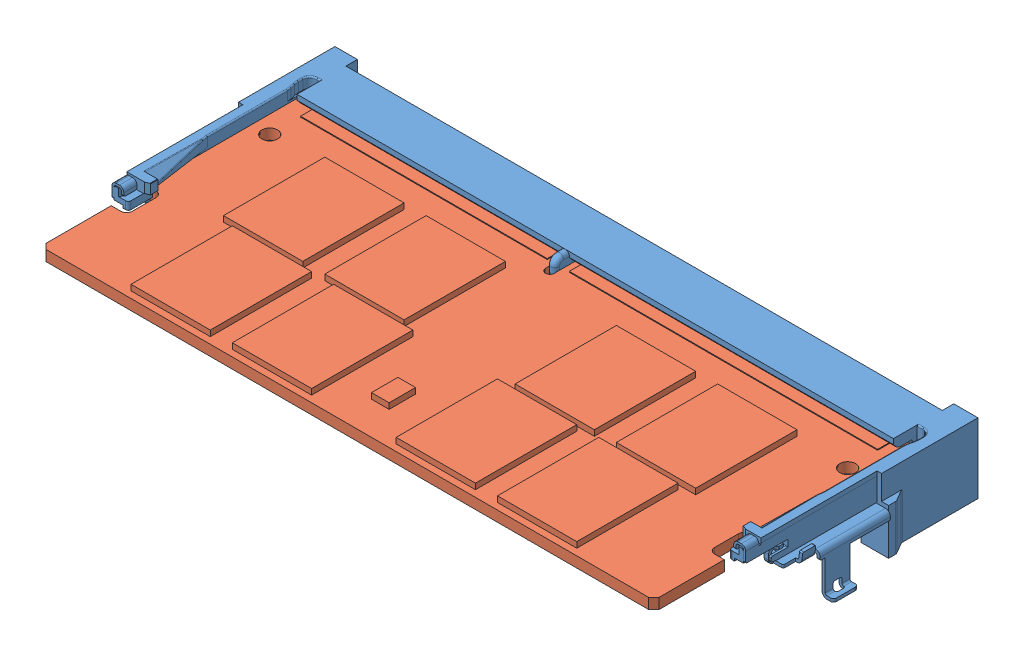
SolidWorks assembly Assembly, configuration Default. Lengths in mm.
Overall size (69.6 2.5 30).
2 component instances, 2 part files, 6 mates.
Components (placement in the parent):
- c-2309411-1-1-3d-1: c-2309411-1-1-3d [Default] at (0 4.0552 20.845) size (77.02 8.49 25.85) (hidden)
- DDR4-Board-1: DDR4-Board [Default] at (0 5.5801 15.094) x (-1 0 0) z (0 1 0) size (69.6 30 2.5)
Mates (geometry in assembly coordinates):
- Coincident2: coincident: plane of c-2309411-1-1-3d-1 through (0 4.0552 20.845) normal (1 0 0); plane of assembly through (0 0 0) normal (1 0 0)
- Coincident3: coincident: plane of c-2309411-1-1-3d-1 through (37.554 0 13.395) normal (0 -1 0); plane of assembly through (0 0 0) normal (0 1 0)
- Coincident4: coincident: plane of c-2309411-1-1-3d-1 through (0 4.0552 0) normal (0 0 1); plane of assembly through (0 0 0) normal (0 0 1)
- Width4: width: plane of c-2309411-1-1-3d-1 through (-34.95 0.0802 19.125) normal (1 0 0); plane of c-2309411-1-1-3d-1 through (34.95 0.0802 5.945) normal (-1 0 0); plane of DDR4-Board-1 through (-34.8 6.7801 -1.1019) normal (-1 0 0); plane of DDR4-Board-1 through (34.8 6.7801 -1.1019) normal (1 0 0)
- Width5: width: plane of DDR4-Board-1 through (0 5.5801 13.2981) normal (0 -1 0); plane of DDR4-Board-1 through (0 6.7801 13.2981) normal (0 1 0); plane of c-2309411-1-1-3d-1 through (0 5.5002 20.845) normal (0 1 0); plane of c-2309411-1-1-3d-1 through (-34.95 6.8601 -0.255) normal (0 -1 0)
- Coincident5: coincident: plane of c-2309411-1-1-3d-1 through (0 0.0802 18.094) normal (0 0 -1); plane of DDR4-Board-1 through (36.55 5.5801 18.094) normal (0 0 1)
